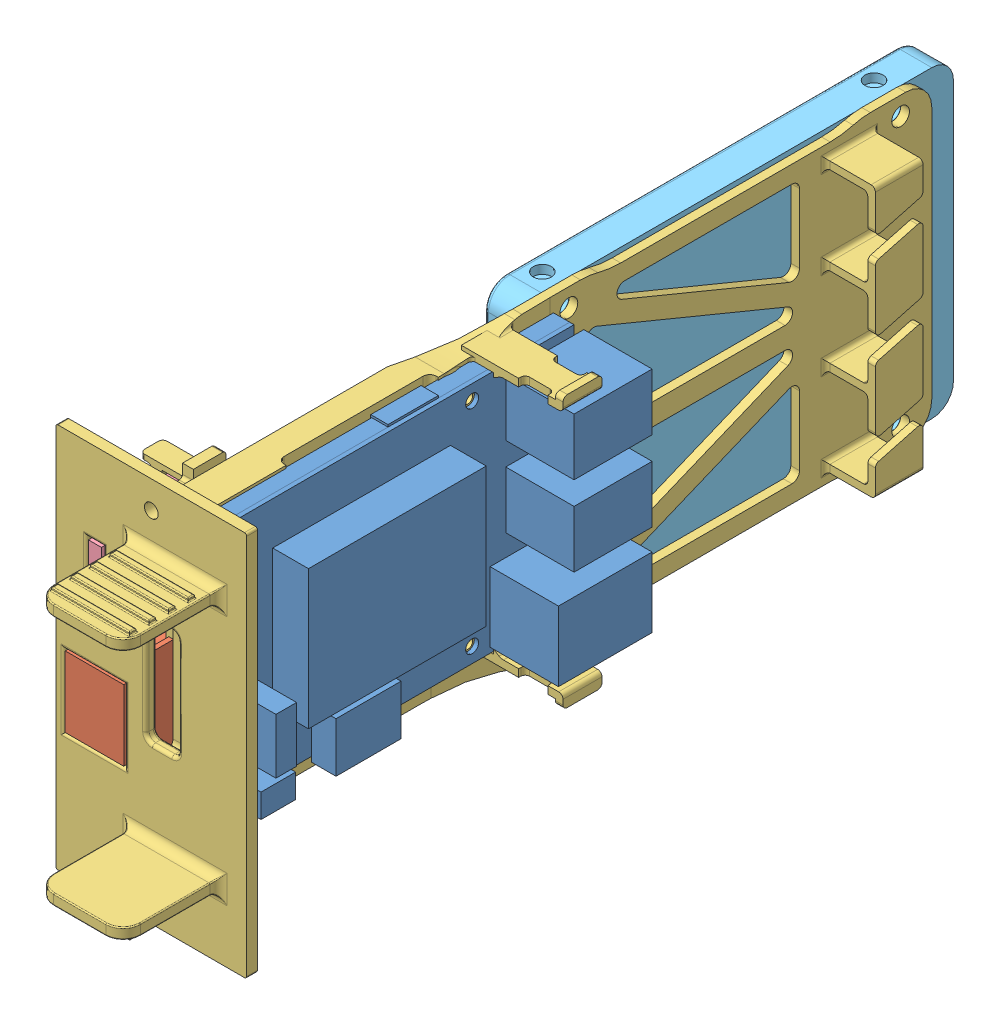
SolidWorks assembly Assem1, configuration Default. Lengths in mm.
Overall size (44 88.9 208.5).
5 component instances, 5 part files, 15 mates.
Components (placement in the parent):
- ODroid_C2.2-1: ODroid_C2.2 [Default] at (4.5 4 -49.5) x (0 0 1) z (1 0 0) size (87.25 57.65 20.75)
- POE-1: POE [Default] at (-5.25 -8 -39.305) x (0 0 -1) z (-1 0 0) size (74.68 25.1 17.85)
- Rack_base-2: Rack_base [Default] x (-1 0 0) z (0 0 -1) size (44 88.9 201.5)
- ODroid-UART-1: ODroid-UART [Default] at (-11.5 21 -1) x (0 0 -1) z (0 1 0) size (27.4 6.3 13.57)
- SSD-1: SSD [Default] at (-1.5 0 -86.5) x (0 0 -1) z (-1 0 0) size (100 70.15 8.25)
Mates (geometry in assembly coordinates):
- Coincident12: coincident anti-aligned: plane of Rack_base-2 through (0 0 0) normal (-1 0 0); plane of assembly through (0 0 0) normal (1 0 0)
- Distance7: distance = 0 mm aligned: plane of Rack_base-2; plane of assembly through (0 0 0) normal (0 1 0)
- Coincident3: coincident anti-aligned: plane of Rack_base-2 through (0 0 0) normal (0 0 -1); plane of assembly through (0 0 0) normal (0 0 1)
- Distance1: distance = 7 mm anti-aligned: plane of Rack_base-2 through (0 0 0) normal (0 0 -1); plane of ODroid_C2.2-1 through (0.75 -23.975 -7) normal (0 0 1)
- Distance6: distance = 4.5 mm anti-aligned: plane of ODroid_C2.2-1 through (4.5 4 -49.5) normal (1 0 0); plane of Rack_base-2 through (0 0 0) normal (-1 0 0)
- Distance16: distance = 4 mm anti-aligned: plane of ODroid_C2.2-1; plane of Rack_base-2
- Distance3: distance = 9.75 mm anti-aligned: plane of POE-1 through (-5.25 -8 -39.305) normal (-1 0 0); plane of ODroid_C2.2-1 through (4.5 4 -49.5) normal (1 0 0)
- Coincident17: coincident aligned: plane of POE-1 through (-19.85 -16.15 0) normal (0 0 1); plane of Rack_base-2 through (0 0 0) normal (0 0 1)
- Distance10: distance = 17 mm anti-aligned: plane of ODroid_C2.2-1; plane of ODroid-UART-1 through (-11.5 21 -1) normal (0 1 0)
- Distance8: distance = 1 mm anti-aligned: plane of ODroid-UART-1; plane of Rack_base-2 through (0 0 0) normal (0 0 1)
- Distance11: distance = 16 mm anti-aligned: plane of ODroid-UART-1; plane of ODroid_C2.2-1 through (4.5 4 -49.5) normal (1 0 0)
- Distance12: distance = 12 mm aligned: plane of POE-1; plane of ODroid_C2.2-1
- Distance14: distance = 6 mm anti-aligned: plane of ODroid_C2.2-1 through (4.5 4 -49.5) normal (1 0 0); plane of SSD-1 through (-1.5 0 -86.5) normal (-1 0 0)
- Distance13: distance = 37 mm anti-aligned: plane of ODroid_C2.2-1; plane of SSD-1
- Distance17: distance = 0 mm anti-aligned: plane of Rack_base-2; plane of SSD-1
